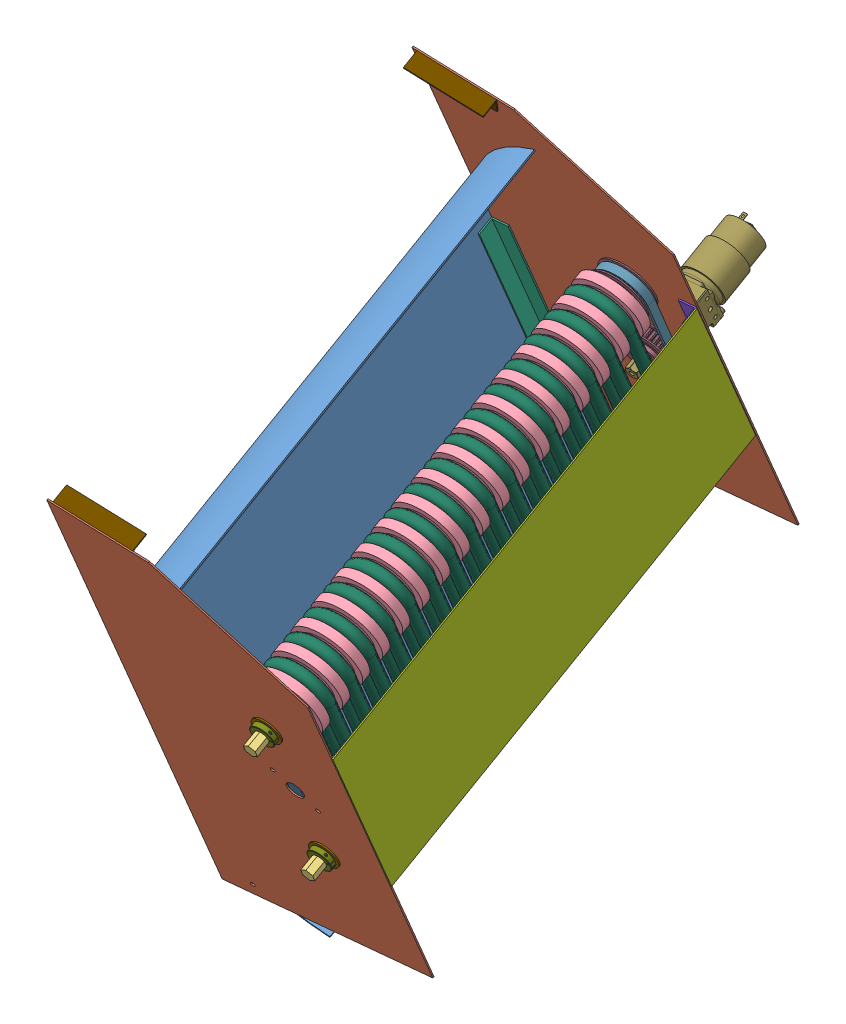
SolidWorks assembly Intake, configuration Default. Lengths in mm.
Overall size (276.05 713.26 729.62).
113 component instances, 18 part files, 72 mates.
Components (placement in the parent):
- Intake Backing Plate-1: Intake Backing Plate [Default] at (267.5638 496.0079 926.5936) x (0.99653 0.019071 -0.081021) z (0.081944 -0.395577 0.91477) size (109.09 472.18 508)
- Intake Side Plate-1: Intake Side Plate [Default] at (267.4399 406.4641 1443.2139) x (0.081944 -0.395577 0.91477) z (-0.99653 -0.019071 0.081021) size (1.59 534.82 227.08)
- Intake Side Plate-2: Intake Side Plate [Default] at (225.6825 608.0454 977.0587) x (0.081944 -0.395577 0.91477) z (-0.99653 -0.019071 0.081021) size (1.59 534.82 227.08)
- 2017 Robot Intake Asm-1: 2017 Robot Intake Asm [Default] at (265.4824 506.0556 903.3584) x (0.899831 0.423969 0.102733) z (0.081944 -0.395577 0.91477) size (100.15 100.15 558.8)
  - Hex Shaft 22in for intake-2: Hex Shaft 22in for intake [Default] at origin size (14.66 12.7 558.8)
  - Banebots T40P 2-875-1: Banebots T40P 2-875 [Default] at (0 0 50.8) x (0.513105 -0.858326 0) z (0 0 1) size (73.03 73.03 10.16)
  - Banebots T40P 2-875-2: Banebots T40P 2-875 [Default] at (0 0 78.74) x (0.513105 -0.858326 0) z (0 0 1) size (73.03 73.03 10.16)
  - Banebots T40P 2-875-3: Banebots T40P 2-875 [Default] at (0 0 106.68) x (0.513105 -0.858326 0) z (0 0 1) size (73.03 73.03 10.16)
  - Banebots T40P 2-875-4: Banebots T40P 2-875 [Default] at (0 0 134.62) x (0.513105 -0.858326 0) z (0 0 1) size (73.03 73.03 10.16)
  - Banebots T40P 2-875-5: Banebots T40P 2-875 [Default] at (0 0 162.56) x (0.513105 -0.858326 0) z (0 0 1) size (73.03 73.03 10.16)
  - Banebots T40P 2-875-6: Banebots T40P 2-875 [Default] at (0 0 190.5) x (0.513105 -0.858326 0) z (0 0 1) size (73.03 73.03 10.16)
  - Banebots T40P 2-875-7: Banebots T40P 2-875 [Default] at (0 0 218.44) x (0.513105 -0.858326 0) z (0 0 1) size (73.03 73.03 10.16)
  - Banebots T40P 2-875-8: Banebots T40P 2-875 [Default] at (0 0 246.38) x (0.513105 -0.858326 0) z (0 0 1) size (73.03 73.03 10.16)
  - Banebots T40P 2-875-9: Banebots T40P 2-875 [Default] at (0 0 274.32) x (0.513105 -0.858326 0) z (0 0 1) size (73.03 73.03 10.16)
  - Banebots T40P 2-875-10: Banebots T40P 2-875 [Default] at (0 0 302.26) x (0.513105 -0.858326 0) z (0 0 1) size (73.03 73.03 10.16)
  - Banebots T40P 2-875-11: Banebots T40P 2-875 [Default] at (0 0 330.2) x (0.513105 -0.858326 0) z (0 0 1) size (73.03 73.03 10.16)
  - Banebots T40P 2-875-12: Banebots T40P 2-875 [Default] at (0 0 358.14) x (0.513105 -0.858326 0) z (0 0 1) size (73.03 73.03 10.16)
  - Banebots T40P 2-875-13: Banebots T40P 2-875 [Default] at (0 0 386.08) x (0.513105 -0.858326 0) z (0 0 1) size (73.03 73.03 10.16)
  - Banebots T40P 2-875-14: Banebots T40P 2-875 [Default] at (0 0 414.02) x (0.513105 -0.858326 0) z (0 0 1) size (73.03 73.03 10.16)
  - Banebots T40P 2-875-15: Banebots T40P 2-875 [Default] at (0 0 441.96) x (0.513105 -0.858326 0) z (0 0 1) size (73.03 73.03 10.16)
  - Banebots T40P 2-875-16: Banebots T40P 2-875 [Default] at (0 0 469.9) x (0.513105 -0.858326 0) z (0 0 1) size (73.03 73.03 10.16)
  - Banebots T40P 2-875-17: Banebots T40P 2-875 [Default] at (0 0 497.84) x (0.513105 -0.858326 0) z (0 0 1) size (73.03 73.03 10.16)
  - Banebots T40P 1-875-1: Banebots T40P 1-875 [Default] at (0 0 64.77) x (0.486779 0.873525 0) z (0 0 1) size (47.62 47.62 10.16)
  - Banebots T40P 1-875-2: Banebots T40P 1-875 [Default] at (0 0 92.71) x (0.486779 0.873525 0) z (0 0 1) size (47.62 47.62 10.16)
  - Banebots T40P 1-875-3: Banebots T40P 1-875 [Default] at (0 0 120.65) x (0.486779 0.873525 0) z (0 0 1) size (47.62 47.62 10.16)
  - Banebots T40P 1-875-4: Banebots T40P 1-875 [Default] at (0 0 148.59) x (0.486779 0.873525 0) z (0 0 1) size (47.62 47.62 10.16)
  - Banebots T40P 1-875-5: Banebots T40P 1-875 [Default] at (0 0 176.53) x (0.486779 0.873525 0) z (0 0 1) size (47.62 47.62 10.16)
  - Banebots T40P 1-875-6: Banebots T40P 1-875 [Default] at (0 0 204.47) x (0.486779 0.873525 0) z (0 0 1) size (47.62 47.62 10.16)
  - Banebots T40P 1-875-7: Banebots T40P 1-875 [Default] at (0 0 232.41) x (0.486779 0.873525 0) z (0 0 1) size (47.62 47.62 10.16)
  - Banebots T40P 1-875-8: Banebots T40P 1-875 [Default] at (0 0 260.35) x (0.486779 0.873525 0) z (0 0 1) size (47.62 47.62 10.16)
  - Banebots T40P 1-875-9: Banebots T40P 1-875 [Default] at (0 0 288.29) x (0.486779 0.873525 0) z (0 0 1) size (47.62 47.62 10.16)
  - Banebots T40P 1-875-10: Banebots T40P 1-875 [Default] at (0 0 316.23) x (0.486779 0.873525 0) z (0 0 1) size (47.62 47.62 10.16)
  - Banebots T40P 1-875-11: Banebots T40P 1-875 [Default] at (0 0 344.17) x (0.486779 0.873525 0) z (0 0 1) size (47.62 47.62 10.16)
  - Banebots T40P 1-875-12: Banebots T40P 1-875 [Default] at (0 0 372.11) x (0.486779 0.873525 0) z (0 0 1) size (47.62 47.62 10.16)
  - Banebots T40P 1-875-13: Banebots T40P 1-875 [Default] at (0 0 400.05) x (0.486779 0.873525 0) z (0 0 1) size (47.62 47.62 10.16)
  - Banebots T40P 1-875-14: Banebots T40P 1-875 [Default] at (0 0 427.99) x (0.486779 0.873525 0) z (0 0 1) size (47.62 47.62 10.16)
  - Banebots T40P 1-875-15: Banebots T40P 1-875 [Default] at (0 0 455.93) x (0.486779 0.873525 0) z (0 0 1) size (47.62 47.62 10.16)
  - Banebots T40P 1-875-16: Banebots T40P 1-875 [Default] at (0 0 483.87) x (0.486779 0.873525 0) z (0 0 1) size (47.62 47.62 10.16)
- 2017 Robot Intake Asm-2: 2017 Robot Intake Asm [Default] at (268.0385 666.7685 972.6272) x (0.830685 -0.480042 -0.281998) z (0.081944 -0.395577 0.91477) size (100.15 100.15 558.8)
  - Hex Shaft 22in for intake-2: Hex Shaft 22in for intake [Default] at origin size (14.66 12.7 558.8)
  - Banebots T40P 2-875-1: Banebots T40P 2-875 [Default] at (0 0 50.8) x (0.513105 -0.858326 0) z (0 0 1) size (73.03 73.03 10.16)
  - Banebots T40P 2-875-2: Banebots T40P 2-875 [Default] at (0 0 78.74) x (0.513105 -0.858326 0) z (0 0 1) size (73.03 73.03 10.16)
  - Banebots T40P 2-875-3: Banebots T40P 2-875 [Default] at (0 0 106.68) x (0.513105 -0.858326 0) z (0 0 1) size (73.03 73.03 10.16)
  - Banebots T40P 2-875-4: Banebots T40P 2-875 [Default] at (0 0 134.62) x (0.513105 -0.858326 0) z (0 0 1) size (73.03 73.03 10.16)
  - Banebots T40P 2-875-5: Banebots T40P 2-875 [Default] at (0 0 162.56) x (0.513105 -0.858326 0) z (0 0 1) size (73.03 73.03 10.16)
  - Banebots T40P 2-875-6: Banebots T40P 2-875 [Default] at (0 0 190.5) x (0.513105 -0.858326 0) z (0 0 1) size (73.03 73.03 10.16)
  - Banebots T40P 2-875-7: Banebots T40P 2-875 [Default] at (0 0 218.44) x (0.513105 -0.858326 0) z (0 0 1) size (73.03 73.03 10.16)
  - Banebots T40P 2-875-8: Banebots T40P 2-875 [Default] at (0 0 246.38) x (0.513105 -0.858326 0) z (0 0 1) size (73.03 73.03 10.16)
  - Banebots T40P 2-875-9: Banebots T40P 2-875 [Default] at (0 0 274.32) x (0.513105 -0.858326 0) z (0 0 1) size (73.03 73.03 10.16)
  - Banebots T40P 2-875-10: Banebots T40P 2-875 [Default] at (0 0 302.26) x (0.513105 -0.858326 0) z (0 0 1) size (73.03 73.03 10.16)
  - Banebots T40P 2-875-11: Banebots T40P 2-875 [Default] at (0 0 330.2) x (0.513105 -0.858326 0) z (0 0 1) size (73.03 73.03 10.16)
  - Banebots T40P 2-875-12: Banebots T40P 2-875 [Default] at (0 0 358.14) x (0.513105 -0.858326 0) z (0 0 1) size (73.03 73.03 10.16)
  - Banebots T40P 2-875-13: Banebots T40P 2-875 [Default] at (0 0 386.08) x (0.513105 -0.858326 0) z (0 0 1) size (73.03 73.03 10.16)
  - Banebots T40P 2-875-14: Banebots T40P 2-875 [Default] at (0 0 414.02) x (0.513105 -0.858326 0) z (0 0 1) size (73.03 73.03 10.16)
  - Banebots T40P 2-875-15: Banebots T40P 2-875 [Default] at (0 0 441.96) x (0.513105 -0.858326 0) z (0 0 1) size (73.03 73.03 10.16)
  - Banebots T40P 2-875-16: Banebots T40P 2-875 [Default] at (0 0 469.9) x (0.513105 -0.858326 0) z (0 0 1) size (73.03 73.03 10.16)
  - Banebots T40P 2-875-17: Banebots T40P 2-875 [Default] at (0 0 497.84) x (0.513105 -0.858326 0) z (0 0 1) size (73.03 73.03 10.16)
  - Banebots T40P 1-875-1: Banebots T40P 1-875 [Default] at (0 0 64.77) x (0.486779 0.873525 0) z (0 0 1) size (47.62 47.62 10.16)
  - Banebots T40P 1-875-2: Banebots T40P 1-875 [Default] at (0 0 92.71) x (0.486779 0.873525 0) z (0 0 1) size (47.62 47.62 10.16)
  - Banebots T40P 1-875-3: Banebots T40P 1-875 [Default] at (0 0 120.65) x (0.486779 0.873525 0) z (0 0 1) size (47.62 47.62 10.16)
  - Banebots T40P 1-875-4: Banebots T40P 1-875 [Default] at (0 0 148.59) x (0.486779 0.873525 0) z (0 0 1) size (47.62 47.62 10.16)
  - Banebots T40P 1-875-5: Banebots T40P 1-875 [Default] at (0 0 176.53) x (0.486779 0.873525 0) z (0 0 1) size (47.62 47.62 10.16)
  - Banebots T40P 1-875-6: Banebots T40P 1-875 [Default] at (0 0 204.47) x (0.486779 0.873525 0) z (0 0 1) size (47.62 47.62 10.16)
  - Banebots T40P 1-875-7: Banebots T40P 1-875 [Default] at (0 0 232.41) x (0.486779 0.873525 0) z (0 0 1) size (47.62 47.62 10.16)
  - Banebots T40P 1-875-8: Banebots T40P 1-875 [Default] at (0 0 260.35) x (0.486779 0.873525 0) z (0 0 1) size (47.62 47.62 10.16)
  - Banebots T40P 1-875-9: Banebots T40P 1-875 [Default] at (0 0 288.29) x (0.486779 0.873525 0) z (0 0 1) size (47.62 47.62 10.16)
  - Banebots T40P 1-875-10: Banebots T40P 1-875 [Default] at (0 0 316.23) x (0.486779 0.873525 0) z (0 0 1) size (47.62 47.62 10.16)
  - Banebots T40P 1-875-11: Banebots T40P 1-875 [Default] at (0 0 344.17) x (0.486779 0.873525 0) z (0 0 1) size (47.62 47.62 10.16)
  - Banebots T40P 1-875-12: Banebots T40P 1-875 [Default] at (0 0 372.11) x (0.486779 0.873525 0) z (0 0 1) size (47.62 47.62 10.16)
  - Banebots T40P 1-875-13: Banebots T40P 1-875 [Default] at (0 0 400.05) x (0.486779 0.873525 0) z (0 0 1) size (47.62 47.62 10.16)
  - Banebots T40P 1-875-14: Banebots T40P 1-875 [Default] at (0 0 427.99) x (0.486779 0.873525 0) z (0 0 1) size (47.62 47.62 10.16)
  - Banebots T40P 1-875-15: Banebots T40P 1-875 [Default] at (0 0 455.93) x (0.486779 0.873525 0) z (0 0 1) size (47.62 47.62 10.16)
  - Banebots T40P 1-875-16: Banebots T40P 1-875 [Default] at (0 0 483.87) x (0.486779 0.873525 0) z (0 0 1) size (47.62 47.62 10.16)
- Intake Box Spine-1: Intake Box Spine [Default] at (156.5672 443.6882 1469.2427) x (-0.014604 -0.918235 -0.395767) z (0.081944 -0.395577 0.91477) size (165.1 19.05 19.05)
- Intake Box Spine-2: Intake Box Spine [Default] at (114.9398 644.6415 1004.5396) x (-0.014604 -0.918235 -0.395767) z (-0.99653 -0.019071 0.081021) size (165.1 19.05 19.05)
- Intake Front Plate-1: Intake Front Plate [Default] at (359.3957 476.746 1189.4388) x (0.99653 0.019071 -0.081021) z (0.081944 -0.395577 0.91477) size (1.59 178.82 508)
- Intake Box Front Rail-1: Intake Box Front Rail [Default] at (378.7735 294.7998 1384.9534) x (0.014604 0.918235 0.395767) z (0.081944 -0.395577 0.91477) size (177.8 19.05 19.05)
- Intake Box Front Rail-2: Intake Box Front Rail [Default] at (337.1461 495.7531 920.2503) x (0.014604 0.918235 0.395767) z (0.99653 0.019071 -0.081021) size (177.8 19.05 19.05)
- .5 hex bearing 1.125 od-1: .5 hex bearing 1.125 od [Default] at (312.0022 454.5367 1463.4117) x (-0.428473 0.81472 0.390694) z (-0.899831 -0.423969 -0.102733) size (31.12 7.92 31.12)
- .5 hex bearing 1.125 od-2: .5 hex bearing 1.125 od [Default] at (309.4461 293.8238 1394.143) x (0.99261 0.114822 -0.039264) z (-0.089504 0.911227 0.402063) size (31.12 7.92 31.12)
- .5 hex bearing 1.125 od-3: .5 hex bearing 1.125 od [Default] at (267.3088 497.2388 923.7473) x (-0.56504 -0.774528 -0.284317) z (-0.820984 0.493584 0.286985) size (31.12 7.92 31.12)
- .5 hex bearing 1.125 od-4: .5 hex bearing 1.125 od [Default] at (269.8649 657.9517 993.016) x (0.550679 0.782993 0.289264) z (0.830685 -0.480042 -0.281998) size (31.12 7.92 31.12)
- Intake Drive Belt-1: Intake Drive Belt [Default] at (308.4889 298.4447 1383.4571) x (-0.081944 0.395577 -0.91477) z (0.99653 0.019071 -0.081021) size (9 225.82 50.8)
- 217-3229-1: 217-3229 [Default] at (308.1201 300.2248 1379.3406) x (0.996511 0.017916 -0.081518) z (0.081944 -0.395577 0.91477) size (51 51 14.5)
- 217-3229-2: 217-3229 [Default] at (310.6762 460.9377 1448.6093) x (0.995266 -0.015644 -0.095919) z (0.081944 -0.395577 0.91477) size (51 51 14.5)
- VEXpro_VersaPlanetary_with_RS775-1: VEXpro_VersaPlanetary_with_RS775 [Default] at (265.5669 594.6561 925.2535) x (-0.99653 -0.019071 0.081021) z (-0.081944 0.395577 -0.91477) size (46.2 46.2 166.9)
- 217-3231-3: 217-3231 [Default] at (269.9495 573.4997 974.1777) x (0.855718 -0.442601 -0.26805) z (0.081944 -0.395577 0.91477) size (60 60 14.5)
- 217-3231-4: 217-3231 [Default] at (271.1909 651.5506 1007.8184) x (-0.06156 -0.918113 -0.391509) z (0.081944 -0.395577 0.91477) size (60 60 14.5)
- Primary Intake Drive Belt-1: Primary Intake Drive Belt [Default] at (269.5807 575.2798 970.0612) x (0.081944 -0.395577 0.91477) z (-0.996304 -0.008774 0.085453) size (9 143.42 58.42)
- Conveyor Tube Belt-1: Conveyor Tube Belt [Default] at (335.6066 313.2132 1348.1913) x (0.081944 -0.395577 0.91477) z (-0.99653 -0.019071 0.081021) size (12.94 248.05 73.15)
- Conveyor Tube Belt-2: Conveyor Tube Belt [Default] at (333.3171 324.2657 1322.6327) x (0.081944 -0.395577 0.91477) z (-0.99653 -0.019071 0.081021) size (12.94 248.05 73.15)
- Conveyor Tube Belt-3: Conveyor Tube Belt [Default] at (331.0276 335.3181 1297.074) x (0.081944 -0.395577 0.91477) z (-0.99653 -0.019071 0.081021) size (12.94 248.05 73.15)
- Conveyor Tube Belt-4: Conveyor Tube Belt [Default] at (328.7381 346.3705 1271.5153) x (0.081944 -0.395577 0.91477) z (-0.99653 -0.019071 0.081021) size (12.94 248.05 73.15)
- Conveyor Tube Belt-5: Conveyor Tube Belt [Default] at (326.4485 357.423 1245.9567) x (0.081944 -0.395577 0.91477) z (-0.99653 -0.019071 0.081021) size (12.94 248.05 73.15)
- Conveyor Tube Belt-6: Conveyor Tube Belt [Default] at (324.159 368.4754 1220.398) x (0.081944 -0.395577 0.91477) z (-0.99653 -0.019071 0.081021) size (12.94 248.05 73.15)
- Conveyor Tube Belt-7: Conveyor Tube Belt [Default] at (321.8695 379.5278 1194.8393) x (0.081944 -0.395577 0.91477) z (-0.99653 -0.019071 0.081021) size (12.94 248.05 73.15)
- Conveyor Tube Belt-8: Conveyor Tube Belt [Default] at (319.58 390.5803 1169.2807) x (0.081944 -0.395577 0.91477) z (-0.99653 -0.019071 0.081021) size (12.94 248.05 73.15)
- Conveyor Tube Belt-9: Conveyor Tube Belt [Default] at (317.2905 401.6327 1143.722) x (0.081944 -0.395577 0.91477) z (-0.99653 -0.019071 0.081021) size (12.94 248.05 73.15)
- Conveyor Tube Belt-10: Conveyor Tube Belt [Default] at (315.001 412.6851 1118.1633) x (0.081944 -0.395577 0.91477) z (-0.99653 -0.019071 0.081021) size (12.94 248.05 73.15)
- Conveyor Tube Belt-11: Conveyor Tube Belt [Default] at (312.7115 423.7376 1092.6047) x (0.081944 -0.395577 0.91477) z (-0.99653 -0.019071 0.081021) size (12.94 248.05 73.15)
- Conveyor Tube Belt-12: Conveyor Tube Belt [Default] at (310.422 434.79 1067.046) x (0.081944 -0.395577 0.91477) z (-0.99653 -0.019071 0.081021) size (12.94 248.05 73.15)
- Conveyor Tube Belt-13: Conveyor Tube Belt [Default] at (308.1325 445.8424 1041.4873) x (0.081944 -0.395577 0.91477) z (-0.99653 -0.019071 0.081021) size (12.94 248.05 73.15)
- Conveyor Tube Belt-14: Conveyor Tube Belt [Default] at (305.843 456.8949 1015.9287) x (0.081944 -0.395577 0.91477) z (-0.99653 -0.019071 0.081021) size (12.94 248.05 73.15)
- Conveyor Tube Belt-15: Conveyor Tube Belt [Default] at (303.5535 467.9473 990.37) x (0.081944 -0.395577 0.91477) z (-0.99653 -0.019071 0.081021) size (12.94 248.05 73.15)
- Conveyor Tube Belt-16: Conveyor Tube Belt [Default] at (301.264 478.9997 964.8113) x (0.081944 -0.395577 0.91477) z (-0.99653 -0.019071 0.081021) size (12.94 248.05 73.15)
- 217-2737 Shaft Collar-1: 217-2737 Shaft Collar [Default] at (312.2624 453.2807 1466.3161) x (0.996375 0.011471 -0.084293) z (0.081944 -0.395577 0.91477) size (25.39 25.4 7.82)
- 217-2737 Shaft Collar-2: 217-2737 Shaft Collar [Default] at (309.7063 292.5678 1397.0473) x (0.98642 0.163282 -0.017753) z (0.081944 -0.395577 0.91477) size (25.39 25.4 7.82)
- 217-2737 Shaft Collar-3: 217-2737 Shaft Collar [Default] at (267.0486 498.4947 920.8429) x (-0.325925 0.856753 0.399685) z (-0.081944 0.395577 -0.91477) size (25.39 25.4 7.82)
- 217-2737 Shaft Collar-4: 217-2737 Shaft Collar [Default] at (269.6047 659.2076 990.1116) x (-0.484522 0.786277 0.383415) z (-0.081944 0.395577 -0.91477) size (25.39 25.4 7.82)
- 1-2 Intake brace-2: 1-2 Intake brace [Default] at (191.6385 180.3136 1348.4347) x (-0.081944 0.395577 -0.91477) z (0.475776 0.822043 0.31286) size (19.05 19.05 12.7)
- 1-2 Intake brace-7: 1-2 Intake brace [Default] at (147.647 378.4748 889.8044) x (-0.694326 0.635805 0.33714) z (0.71498 0.662775 0.22256) size (19.05 19.05 12.7)
- 3-4 brace for top intake-1: 3-4 brace for top intake [Default] at (123.2248 854.4517 1115.3514) x (-0.272028 -0.891882 -0.361312) z (0.958794 -0.219235 -0.180692) size (19.05 19.05 81.28)
- 3-4 brace for top intake-2: 3-4 brace for top intake [Default] at (158.109 644.0437 1555.7451) x (-0.081944 0.395577 -0.91477) z (0.958794 -0.219235 -0.180692) size (19.05 19.05 81.28)
Mates (geometry in assembly coordinates):
- Coincident1: coincident anti-aligned: plane of Intake Backing Plate-1 through (156.7121 452.8005 1473.1702) normal (0.081944 -0.395577 0.91477); plane of Intake Side Plate-1 through (267.4399 406.4641 1443.2139) normal (-0.081944 0.395577 -0.91477)
- Coincident3: coincident anti-aligned: plane of Intake Backing Plate-1 through (270.1199 656.7208 995.8623) normal (-0.081944 0.395577 -0.91477); plane of Intake Side Plate-2 through (225.8126 607.4175 978.5109) normal (0.081944 -0.395577 0.91477)
- Concentric6: concentric aligned: cylinder of Intake Side Plate-2 through (267.5638 496.0079 926.5936) axis (-0.081944 0.395577 -0.91477) radius 14.2875; cylinder of 2017 Robot Intake Asm-1/Banebots T40P 2-875-1 through (270.4777 481.9412 959.1228) axis (-0.081944 0.395577 -0.91477) radius 36.5125
- Concentric7: concentric aligned: cylinder of Intake Side Plate-2 through (270.1199 656.7208 995.8623) axis (-0.081944 0.395577 -0.91477) radius 14.2875; cylinder of 2017 Robot Intake Asm-2/Banebots T40P 2-875-17 through (309.6659 465.8152 1437.3302) axis (-0.081944 0.395577 -0.91477) radius 36.5125
- Coincident4: coincident aligned: plane of 2017 Robot Intake Asm-1/Banebots T40P 2-875-1 through (269.9053 484.7043 952.7331) normal (-0.081944 0.395577 -0.91477); plane of 2017 Robot Intake Asm-2/Banebots T40P 2-875-1 through (272.4614 645.4172 1022.0019) normal (-0.081944 0.395577 -0.91477)
- Width1: width anti-aligned: plane of 2017 Robot Intake Asm-1/Banebots T40P 2-875-1 through (269.6451 485.9603 949.8288) normal (-0.081944 0.395577 -0.91477); plane of 2017 Robot Intake Asm-1/Banebots T40P 2-875-17 through (307.1098 305.1023 1368.0615) normal (0.081944 -0.395577 0.91477); plane of Intake Side Plate-1 through (267.57 405.8362 1444.6661) normal (0.081944 -0.395577 0.91477); plane of Intake Side Plate-2 through (225.6825 608.0454 977.0587) normal (-0.081944 0.395577 -0.91477)
- Coincident5: coincident anti-aligned: plane of Intake Side Plate-1 through (267.4399 406.4641 1443.2139) normal (-0.081944 0.395577 -0.91477); plane of Intake Box Spine-1 through (154.156 292.0876 1403.9014) normal (0.081944 -0.395577 0.91477)
- Coincident6: coincident anti-aligned: plane of Intake Backing Plate-1 through (154.156 292.0876 1403.9014) normal (0.99653 0.019071 -0.081021); plane of Intake Box Spine-1 through (152.595 299.6234 1386.4751) normal (-0.99653 -0.019071 0.081021)
- Coincident9: coincident anti-aligned: plane of Intake Side Plate-2 through (225.8126 607.4175 978.5109) normal (0.081944 -0.395577 0.91477); plane of Intake Box Spine-2 through (131.5125 493.4043 937.6549) normal (-0.081944 0.395577 -0.91477)
- Coincident10: coincident: line of Intake Backing Plate-1 through (154.156 292.0876 1403.9014) axis (-0.081944 0.395577 -0.91477); plane of Intake Box Spine-2 through (112.5286 493.041 939.1984) normal (-0.014604 -0.918235 -0.395767)
- Coincident11: coincident anti-aligned: plane of Intake Side Plate-1 through (384.4236 641.233 1535.9921) normal (0.99653 0.019071 -0.081021); plane of Intake Front Plate-1 through (359.3957 476.746 1189.4388) normal (-0.99653 -0.019071 0.081021)
- Coincident12: coincident aligned: plane of Intake Side Plate-1 through (267.57 405.8362 1444.6661) normal (0.081944 -0.395577 0.91477); plane of Intake Front Plate-1 through (380.4856 294.2021 1386.2769) normal (0.081944 -0.395577 0.91477)
- Coincident14: coincident anti-aligned: plane of Intake Front Plate-1 through (359.3957 476.746 1189.4388) normal (-0.99653 -0.019071 0.081021); plane of Intake Box Front Rail-1 through (379.8091 465.5976 1437.8945) normal (0.99653 0.019071 -0.081021)
- Coincident15: coincident anti-aligned: plane of Intake Side Plate-1 through (267.4399 406.4641 1443.2139) normal (-0.081944 0.395577 -0.91477); plane of Intake Box Front Rail-1 through (381.3702 458.0619 1455.3208) normal (0.081944 -0.395577 0.91477)
- Coincident16: coincident aligned: plane of Intake Front Plate-1 through (380.4856 294.2021 1386.2769) normal (-0.014604 -0.918235 -0.395767); plane of Intake Box Front Rail-1 through (378.7735 294.7998 1384.9534) normal (-0.014604 -0.918235 -0.395767)
- Coincident17: coincident anti-aligned: plane of Intake Side Plate-2 through (225.8126 607.4175 978.5109) normal (0.081944 -0.395577 0.91477); plane of Intake Box Front Rail-2 through (320.7589 658.6519 992.1612) normal (-0.081944 0.395577 -0.91477)
- Coincident18: coincident anti-aligned: plane of Intake Front Plate-1 through (359.3957 476.746 1189.4388) normal (-0.99653 -0.019071 0.081021); plane of Intake Box Front Rail-2 through (339.7428 659.0152 990.6178) normal (0.99653 0.019071 -0.081021)
- Coincident19: coincident aligned: plane of Intake Front Plate-1 through (380.4856 294.2021 1386.2769) normal (-0.014604 -0.918235 -0.395767); plane of Intake Box Front Rail-2 through (337.1461 495.7531 920.2503) normal (-0.014604 -0.918235 -0.395767)
- Concentric9: concentric anti-aligned: cylinder of Intake Side Plate-1 through (311.8773 455.1395 1462.0176) axis (-0.081944 0.395577 -0.91477) radius 14.2875; cylinder of .5 hex bearing 1.125 od-1 through (311.8773 455.1395 1462.0176) axis (0.081944 -0.395577 0.91477) radius 15.5575
- Coincident28: coincident anti-aligned: plane of Intake Side Plate-1 through (267.57 405.8362 1444.6661) normal (0.081944 -0.395577 0.91477); plane of .5 hex bearing 1.125 od-1 through (311.8773 455.1395 1462.0176) normal (-0.081944 0.395577 -0.91477)
- Concentric10: concentric anti-aligned: cylinder of Intake Side Plate-1 through (309.3212 294.4266 1392.7488) axis (-0.081944 0.395577 -0.91477) radius 14.2875; cylinder of .5 hex bearing 1.125 od-2 through (308.7967 296.9586 1386.8936) axis (0.081944 -0.395577 0.91477) radius 14.2875
- Coincident29: coincident anti-aligned: plane of Intake Side Plate-1 through (267.57 405.8362 1444.6661) normal (0.081944 -0.395577 0.91477); plane of .5 hex bearing 1.125 od-2 through (309.3212 294.4266 1392.7488) normal (-0.081944 0.395577 -0.91477)
- Concentric11: concentric aligned: cylinder of Intake Side Plate-2 through (267.5638 496.0079 926.5936) axis (-0.081944 0.395577 -0.91477) radius 14.2875; cylinder of .5 hex bearing 1.125 od-3 through (267.9582 494.1039 930.9967) axis (-0.081944 0.395577 -0.91477) radius 14.2875
- Coincident30: coincident anti-aligned: plane of Intake Side Plate-2 through (225.6825 608.0454 977.0587) normal (-0.081944 0.395577 -0.91477); plane of .5 hex bearing 1.125 od-3 through (267.4337 496.6359 925.1414) normal (0.081944 -0.395577 0.91477)
- Concentric12: concentric aligned: cylinder of Intake Side Plate-2 through (270.1199 656.7208 995.8623) axis (-0.081944 0.395577 -0.91477) radius 14.2875; cylinder of .5 hex bearing 1.125 od-4 through (270.5143 654.8168 1000.2654) axis (-0.081944 0.395577 -0.91477) radius 14.2875
- Coincident31: coincident anti-aligned: plane of Intake Side Plate-2 through (225.6825 608.0454 977.0587) normal (-0.081944 0.395577 -0.91477); plane of .5 hex bearing 1.125 od-4 through (269.9898 657.3488 994.4101) normal (0.081944 -0.395577 0.91477)
- Parallel3: parallel: plane of 2017 Robot Intake Asm-2/Hex Shaft 22in for intake-2 through (319.9195 442.2 1481.7328) normal (0.994734 -0.024231 -0.099585); line of .5 hex bearing 1.125 od-4 through (275.9558 654.4318 990.9483) axis (0.06156 0.918113 0.391509)
- Coincident33: coincident anti-aligned: plane of 2017 Robot Intake Asm-1/Hex Shaft 22in for intake-2 through (305.2528 288.6261 1416.6361) normal (-0.993513 0.040192 0.106378); plane of .5 hex bearing 1.125 od-3 through (261.9384 497.723 933.1009) normal (0.993513 -0.040192 -0.106378)
- Concentric15: concentric anti-aligned: cylinder of Intake Drive Belt-1 through (307.7514 302.0049 1375.2241) axis (0.081944 -0.395577 0.91477) radius 22.225; cylinder of 217-3229-1 through (312.0602 281.2042 1423.3257) axis (-0.081944 0.395577 -0.91477) radius 10.5
- Concentric16: concentric aligned: cylinder of 2017 Robot Intake Asm-1/Banebots T40P 2-875-17 through (307.1098 305.1023 1368.0615) axis (-0.081944 0.395577 -0.91477) radius 36.5125; cylinder of 217-3229-1 through (312.0602 281.2042 1423.3257) axis (-0.081944 0.395577 -0.91477) radius 10.5
- Width3: width aligned: plane of 217-3229-1 through (308.5708 298.0491 1384.3718) normal (-0.081944 0.395577 -0.91477); plane of 217-3229-1 through (307.6694 302.4005 1374.3094) normal (0.081944 -0.395577 0.91477); plane of Intake Drive Belt-1 through (310.3075 462.7178 1444.4929) normal (-0.081944 0.395577 -0.91477); plane of Intake Drive Belt-1 through (311.045 459.1576 1452.7258) normal (0.081944 -0.395577 0.91477)
- Coincident37: coincident aligned: plane of 217-3229-1 through (307.526 303.0927 1372.7085) normal (-0.081944 0.395577 -0.91477); plane of 217-3229-2 through (310.0822 463.8056 1441.9772) normal (-0.081944 0.395577 -0.91477)
- Concentric18: concentric aligned: cylinder of 2017 Robot Intake Asm-2/Banebots T40P 2-875-17 through (309.6659 465.8152 1437.3302) axis (-0.081944 0.395577 -0.91477) radius 36.5125; cylinder of 217-3229-2 through (314.6164 441.917 1492.5944) axis (-0.081944 0.395577 -0.91477) radius 10.5
- Coincident38: coincident anti-aligned: plane of Intake Side Plate-2 through (225.6825 608.0454 977.0587) normal (-0.081944 0.395577 -0.91477); plane of VEXpro_VersaPlanetary_with_RS775-1 through (289.9822 598.9813 967.3791) normal (0.081944 -0.395577 0.91477)
- Concentric19: concentric aligned: cylinder of Intake Side Plate-2 through (286.5144 562.5204 953.6583) axis (-0.081944 0.395577 -0.91477) radius 2.5527; cylinder of VEXpro_VersaPlanetary_with_RS775-1 through (285.1039 569.3293 937.9128) axis (-0.081944 0.395577 -0.91477) radius 2.0193
- Concentric20: concentric aligned: cylinder of Intake Side Plate-2 through (251.2426 594.8193 970.785) axis (-0.081944 0.395577 -0.91477) radius 2.5527; cylinder of VEXpro_VersaPlanetary_with_RS775-1 through (249.8321 601.6282 955.0395) axis (-0.081944 0.395577 -0.91477) radius 2.0193
- Concentric21: concentric aligned: cylinder of VEXpro_VersaPlanetary_with_RS775-1 through (272.1798 562.733 999.0756) axis (0.081944 -0.395577 0.91477) radius 2.5527; cylinder of 217-3231-3 through (265.1982 596.4363 921.1368) axis (0.081944 -0.395577 0.91477) radius 10.5
- Coincident39: coincident anti-aligned: plane of VEXpro_VersaPlanetary_with_RS775-1 through (278.5613 566.2205 1000.0121) normal (0.510913 0.80475 0.302234); plane of 217-3231-3 through (273.7879 575.7419 982.729) normal (-0.510913 -0.80475 -0.302234)
- Concentric22: concentric anti-aligned: cylinder of .5 hex bearing 1.125 od-4 through (270.5143 654.8168 1000.2654) axis (-0.081944 0.395577 -0.91477) radius 14.2875; cylinder of 217-3231-4 through (266.4396 674.4873 954.7775) axis (0.081944 -0.395577 0.91477) radius 10.5
- Coincident40: coincident aligned: plane of 217-3231-3 through (270.5436 570.6317 980.8098) normal (0.081944 -0.395577 0.91477); plane of 217-3231-4 through (271.785 648.6827 1014.4504) normal (0.081944 -0.395577 0.91477)
- Coincident42: coincident anti-aligned: plane of 2017 Robot Intake Asm-2/Hex Shaft 22in for intake-2 through (320.3709 448.9319 1484.6035) normal (0.550679 0.782993 0.289264); plane of 217-3231-4 through (275.2818 653.6547 1016.2873) normal (-0.550679 -0.782993 -0.289264)
- Concentric23: concentric anti-aligned: cylinder of 217-3231-3 through (265.1982 596.4363 921.1368) axis (0.081944 -0.395577 0.91477) radius 10.5; cylinder of Primary Intake Drive Belt-1 through (270.3182 571.7196 978.2942) axis (-0.081944 0.395577 -0.91477) radius 26.035
- Width4: width anti-aligned: plane of 217-3231-3 through (269.4988 575.6753 969.1465) normal (0.081944 -0.395577 0.91477); plane of 217-3231-3 through (270.4002 571.324 979.2089) normal (-0.081944 0.395577 -0.91477); plane of Primary Intake Drive Belt-1 through (269.5807 575.2798 970.0612) normal (-0.081944 0.395577 -0.91477); plane of Primary Intake Drive Belt-1 through (270.3182 571.7196 978.2942) normal (0.081944 -0.395577 0.91477)
- Distance3: distance = 6.35 mm anti-aligned: plane of 217-3229-2 through (310.0822 463.8056 1441.9772) normal (-0.081944 0.395577 -0.91477); plane of 2017 Robot Intake Asm-2/Banebots T40P 2-875-17 through (309.5618 466.3175 1436.1685) normal (0.081944 -0.395577 0.91477)
- Distance4: distance = 6.35 mm anti-aligned: plane of 217-3231-4 through (271.785 648.6827 1014.4504) normal (0.081944 -0.395577 0.91477); plane of 2017 Robot Intake Asm-2/Banebots T40P 2-875-1 through (272.3053 646.1708 1020.2592) normal (-0.081944 0.395577 -0.91477)
- Concentric24: concentric anti-aligned: cylinder of 2017 Robot Intake Asm-2/Banebots T40P 1-875-15 through (306.2316 482.3938 1398.9922) axis (-0.081944 0.395577 -0.91477) radius 23.8125; line of Conveyor Tube Belt-1 through (307.5215 476.1671 1413.3914) axis (0.081944 -0.395577 0.91477)
- Concentric25: concentric anti-aligned: cylinder of 2017 Robot Intake Asm-1/Banebots T40P 1-875-14 through (301.386 332.7334 1304.1648) axis (-0.081944 0.395577 -0.91477) radius 23.8125; line of Conveyor Tube Belt-1 through (304.9654 315.4542 1344.1227) axis (0.081944 -0.395577 0.91477)
- Symmetric1: symmetric aligned: plane of 2017 Robot Intake Asm-2/Banebots T40P 2-875-17 through (308.8333 469.8342 1428.0362) normal (-0.081944 0.395577 -0.91477); plane of 2017 Robot Intake Asm-2/Banebots T40P 2-875-16 through (307.3764 476.8676 1411.7715) normal (0.081944 -0.395577 0.91477); plane of Conveyor Tube Belt-1
- Concentric26: concentric anti-aligned: cylinder of .5 hex bearing 1.125 od-1 through (311.3528 457.6715 1456.1623) axis (0.081944 -0.395577 0.91477) radius 14.2875; cylinder of 217-2737 Shaft Collar-1 through (312.5226 452.0247 1469.2205) axis (-0.081944 0.395577 -0.91477) radius 12.7
- Coincident45: coincident anti-aligned: plane of .5 hex bearing 1.125 od-1 through (312.0022 454.5367 1463.4117) normal (0.081944 -0.395577 0.91477); plane of 217-2737 Shaft Collar-1 through (312.0022 454.5367 1463.4117) normal (-0.081944 0.395577 -0.91477)
- Concentric27: concentric anti-aligned: cylinder of .5 hex bearing 1.125 od-2 through (308.7967 296.9586 1386.8936) axis (0.081944 -0.395577 0.91477) radius 14.2875; cylinder of 217-2737 Shaft Collar-2 through (309.9664 291.3119 1399.9517) axis (-0.081944 0.395577 -0.91477) radius 12.7
- Coincident46: coincident: plane of .5 hex bearing 1.125 od-2 through (309.4461 293.8238 1394.143) normal (0.081944 -0.395577 0.91477); plane of 217-2737 Shaft Collar-2 through (309.4461 293.8238 1394.143) normal (-0.081944 0.395577 -0.91477)
- Concentric28: concentric anti-aligned: cylinder of .5 hex bearing 1.125 od-3 through (267.4337 496.6359 925.1414) axis (-0.081944 0.395577 -0.91477) radius 15.5575; cylinder of 217-2737 Shaft Collar-3 through (266.7884 499.7507 917.9385) axis (0.081944 -0.395577 0.91477) radius 12.7
- Coincident47: coincident: plane of .5 hex bearing 1.125 od-3 through (267.3088 497.2388 923.7473) normal (-0.081944 0.395577 -0.91477); plane of 217-2737 Shaft Collar-3 through (267.3088 497.2388 923.7473) normal (0.081944 -0.395577 0.91477)
- Concentric29: concentric anti-aligned: cylinder of .5 hex bearing 1.125 od-4 through (269.9898 657.3488 994.4101) axis (-0.081944 0.395577 -0.91477) radius 15.5575; cylinder of 217-2737 Shaft Collar-4 through (269.3446 660.4636 987.2072) axis (0.081944 -0.395577 0.91477) radius 12.7
- Coincident48: coincident anti-aligned: plane of .5 hex bearing 1.125 od-4 through (269.8649 657.9517 993.016) normal (-0.081944 0.395577 -0.91477); plane of 217-2737 Shaft Collar-4 through (269.8649 657.9517 993.016) normal (0.081944 -0.395577 0.91477)
- Concentric30: concentric anti-aligned: cylinder of Intake Drive Belt-1 through (310.3075 462.7178 1444.4929) axis (0.081944 -0.395577 0.91477) radius 25.4; circle of 217-3229-2
- Coincident52: coincident anti-aligned: plane of Intake Side Plate-1 through (267.4399 406.4641 1443.2139) normal (-0.081944 0.395577 -0.91477); plane of Intake Box Spine-1 through (154.156 292.0876 1403.9014) normal (0.081944 -0.395577 0.91477)
- Concentric41: concentric anti-aligned: cylinder of 2017 Robot Intake Asm-2/Banebots T40P 2-875-17 through (309.6659 465.8152 1437.3302) axis (-0.081944 0.395577 -0.91477) radius 36.5125; cylinder of .5 hex bearing 1.125 od-1 through (311.8773 455.1395 1462.0176) axis (0.081944 -0.395577 0.91477) radius 15.5575
- Concentric45: concentric anti-aligned: cylinder of Intake Backing Plate-1 through (309.1911 295.0546 1391.2966) axis (-0.081944 0.395577 -0.91477) radius 155.575; cylinder of .5 hex bearing 1.125 od-2 through (309.3212 294.4266 1392.7488) axis (0.081944 -0.395577 0.91477) radius 15.5575
- Concentric46: concentric anti-aligned: cylinder of Intake Backing Plate-1 through (311.7473 455.7675 1460.5654) axis (-0.081944 0.395577 -0.91477) radius 155.575; cylinder of .5 hex bearing 1.125 od-1 through (311.8773 455.1395 1462.0176) axis (0.081944 -0.395577 0.91477) radius 15.5575
- Coincident54: coincident anti-aligned: plane of Intake Backing Plate-1 through (154.156 292.0876 1403.9014) normal (0.99653 0.019071 -0.081021); plane of Intake Box Spine-2 through (112.5286 493.041 939.1984) normal (-0.99653 -0.019071 0.081021)
- Coincident55: coincident anti-aligned: plane of Intake Side Plate-1 through (267.4399 406.4641 1443.2139) normal (-0.081944 0.395577 -0.91477); plane of 1-2 Intake brace-2 through (183.9198 195.9563 1359.6648) normal (0.081944 -0.395577 0.91477)
- Coincident59: coincident: plane of Intake Box Spine-1 through (154.156 292.0876 1403.9014) normal (-0.014604 -0.918235 -0.395767); line of Intake Backing Plate-1 through (154.156 292.0876 1403.9014) axis (-0.081944 0.395577 -0.91477)
- Parallel14: parallel aligned: plane of Intake Backing Plate-1 through (152.574 292.0574 1404.0301) normal (-0.99653 -0.019071 0.081021); plane of Intake Side Plate-2 through (116.3781 838.4838 1088.2347) normal (-0.99653 -0.019071 0.081021)
- Coincident62: coincident anti-aligned: plane of Intake Side Plate-2 through (225.8126 607.4175 978.5109) normal (0.081944 -0.395577 0.91477); plane of 3-4 brace for top intake-1 through (199.5946 844.168 1083.2384) normal (-0.081944 0.395577 -0.91477)
- Coincident63: coincident aligned: plane of Intake Side Plate-2 through (215.9767 841.0203 1078.6743) normal (0.272028 0.891882 0.361312); plane of 3-4 brace for top intake-1 through (201.1556 836.6322 1100.6647) normal (0.272028 0.891882 0.361312)
- Coincident65: coincident: plane of Intake Side Plate-2 through (116.3781 838.4838 1088.2347) normal (-0.99653 -0.019071 0.081021); line of 3-4 brace for top intake-1 through (116.6117 844.3691 1092.4942) axis (-0.081944 0.395577 -0.91477)
- Coincident66: coincident anti-aligned: plane of Intake Side Plate-1 through (267.4399 406.4641 1443.2139) normal (-0.081944 0.395577 -0.91477); plane of 3-4 brace for top intake-2 through (236.0398 626.2243 1541.0584) normal (0.081944 -0.395577 0.91477)
- Coincident67: coincident aligned: plane of Intake Side Plate-1 through (257.7342 639.439 1544.8295) normal (0.272028 0.891882 0.361312); plane of 3-4 brace for top intake-2 through (241.222 643.2146 1547.9414) normal (0.272028 0.891882 0.361312)
- Coincident68: coincident: plane of Intake Side Plate-1 through (158.1355 636.9025 1554.39) normal (-0.99653 -0.019071 0.081021); line of 3-4 brace for top intake-2 through (158.109 644.0437 1555.7451) axis (-0.081944 0.395577 -0.91477)
- Coincident69: coincident anti-aligned: circle of Intake Side Plate-1; cylinder of 1-2 Intake brace-2 through (189.2202 187.4159 1353.7476) axis (-0.081944 0.395577 -0.91477) radius 2.4574
